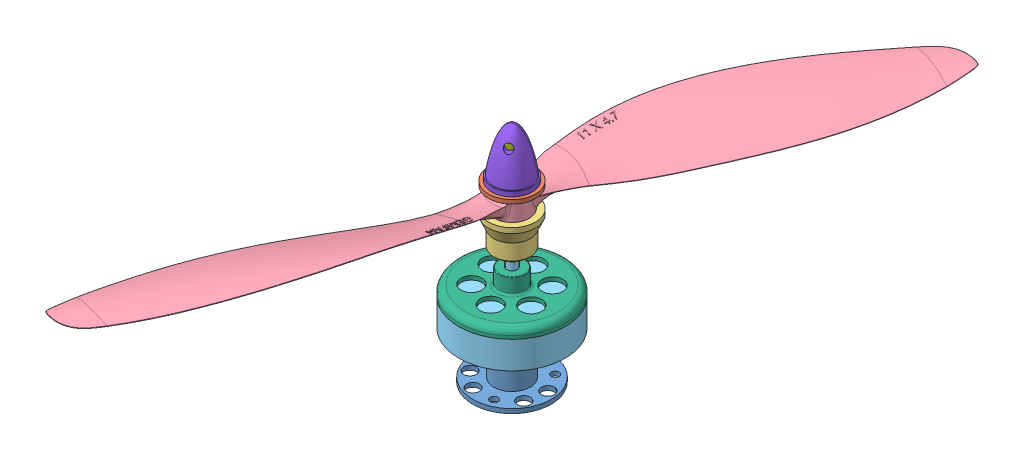
SolidWorks assembly rotor_assembly, configuration Default. Lengths in mm.
Overall size (136.79 85.83 276.18).
8 component instances, 8 part files, 23 mates.
Components (placement in the parent):
- Motor Base Plate-1: Motor Base Plate [Default] at (0 -9.0065 0) x (0.160855 0 -0.986978) z (0 1 0) size (30 30 12.45)
- Arruela-1: Arruela [Default] at (0 55.3235 0) x (-0.84872 0 -0.528843) z (0 1 0) size (18 18 2.5)
- Bucha-1: Bucha [Default] at (0 35.4935 0) x (0.87824 0 0.47822) z (0 1 0) size (18 18 13)
- helice gemfan 11x4-7-1: helice gemfan 11x4-7 [Default] at (0 55.3235 0) x (0.349495 0 -0.936938) z (0.936938 0 0.349495) size (279.15 12.2 41.87)
- Motor Eixo-1: Motor Eixo [Default] at (0 -9.0065 0) x (-0.513141 0 -0.858304) z (0 1 0) size (40.8 40.8 53.5)
- Motor Topblue-1: Motor Topblue [Default] at (0 19.4935 0) x (-0.687158 0 -0.726508) z (0 1 0) size (40.8 40.8 9.7)
- Spiner Shaft-1: Spiner Shaft [Default] at (0 34.4935 0) x (0 1 0) z (0.441152 0 -0.897432) size (40 10.49 10.5)
- spinner porca 2-1: spinner porca 2 [Default] at (0 57.8235 0) x (0.84389 0 -0.536516) z (0.536516 0 0.84389) size (15.5 19 15.5)
Mates (geometry in assembly coordinates):
- Coincident7: coincident: plane of Motor Base Plate-1; line of assembly
- Coincident8: coincident: plane of Motor Base Plate-1; line of assembly
- Coincident9: coincident: plane of Motor Eixo-1; line of assembly
- Coincident10: coincident: plane of Motor Eixo-1; line of assembly
- Coincident12: coincident aligned: plane of Motor Base Plate-1 through (2.4128 -9.0065 -14.8047) normal (0 -1 0); plane of Motor Eixo-1 through (-2.5144 -9.0065 -4.2057) normal (0 -1 0)
- Coincident15: coincident: plane of Motor Topblue-1; line of assembly
- Coincident16: coincident: plane of Motor Topblue-1; line of assembly
- Coincident17: coincident anti-aligned: plane of Motor Eixo-1 through (-1.0263 19.4935 -1.7166) normal (0 1 0); plane of Motor Topblue-1 through (-13.5026 19.4935 -14.2759) normal (0 -1 0)
- Coincident18: coincident: plane of Bucha-1; line of assembly
- Coincident19: coincident: plane of Bucha-1; line of assembly
- Coincident20: coincident: plane of Spiner Shaft-1 through (0 34.4935 0) normal (0.441152 0 -0.897432); line of assembly
- Coincident21: coincident: plane of Spiner Shaft-1; line of assembly
- Coincident22: coincident anti-aligned: plane of Motor Eixo-1 through (0 44.4935 0) normal (0 1 0); plane of Spiner Shaft-1 through (-2.9077 44.4935 1.9482) normal (0 -1 0)
- Distance1: distance = 1 mm aligned: plane of Bucha-1 through (4.3912 35.4935 2.3911) normal (0 -1 0); plane of Spiner Shaft-1 through (2.3558 34.4935 1.158) normal (0 -1 0)
- Coincident24: coincident: plane of helice gemfan 11x4-7-1 through (0 55.3235 0) normal (0.349495 0 -0.936938); line of assembly
- Coincident25: coincident: plane of helice gemfan 11x4-7-1 through (0 55.3235 0) normal (0.936938 0 0.349495); line of assembly
- Coincident26: coincident anti-aligned: plane of Bucha-1 through (7.9042 48.4935 4.304) normal (0 1 0); plane of helice gemfan 11x4-7-1 through (0 48.4935 0) normal (0 -1 0)
- Coincident27: coincident: plane of Arruela-1; line of assembly
- Coincident28: coincident: plane of Arruela-1; line of assembly
- Coincident29: coincident anti-aligned: plane of Arruela-1 through (-2.5462 55.3235 -1.5865) normal (0 -1 0); plane of helice gemfan 11x4-7-1 through (0 55.3235 0) normal (0 1 0)
- Coincident30: coincident: plane of spinner porca 2-1 through (0 57.8235 0) normal (0.536516 0 0.84389); line of assembly
- Coincident31: coincident: plane of spinner porca 2-1 through (0 57.8235 0) normal (0.84389 0 -0.536516); line of assembly
- Coincident32: coincident anti-aligned: plane of Arruela-1 through (-7.6385 57.8235 -4.7596) normal (0 1 0); plane of spinner porca 2-1 through (2.3207 57.8235 -1.4754) normal (0 -1 0)
